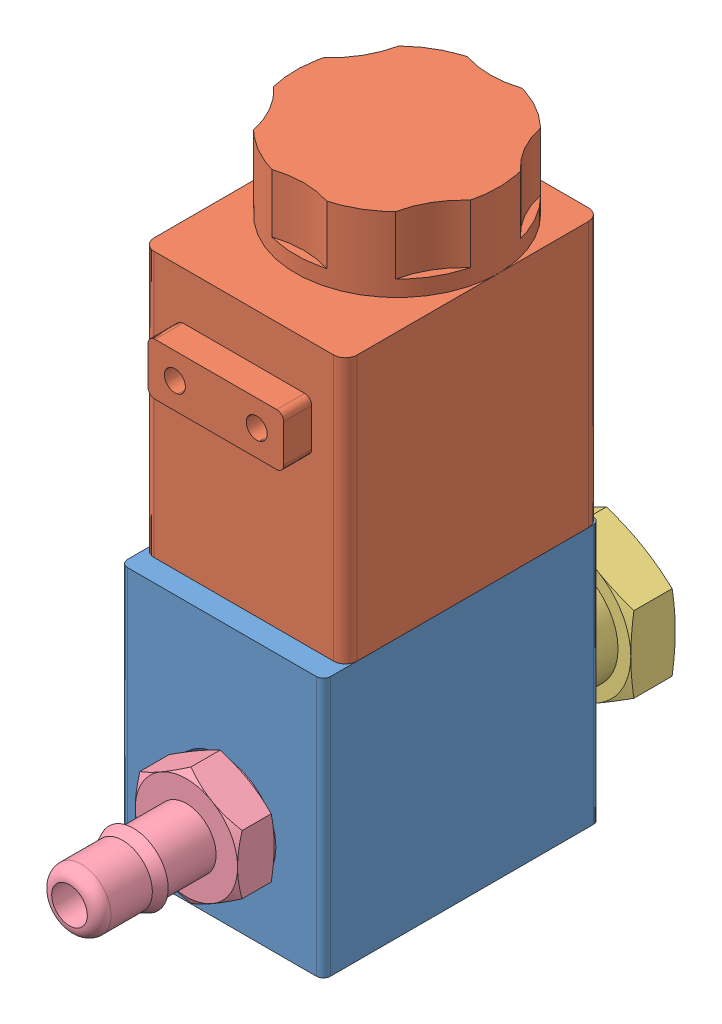
SolidWorks assembly Solenoid Valve Assembly REV1, configuration Default. Lengths in mm.
Overall size (22.05 65.07 58.93).
4 component instances, 4 part files, 9 mates.
Components (placement in the parent):
- Solenoid Valve bottom REV1-1: Solenoid Valve bottom REV1 [Default] at (0.5427 1.4167 38.0636) size (22.05 28.19 30.07)
- Solenoid Valve Top REV1-1: Solenoid Valve Top REV1 [Default] at (0.5427 29.6107 35.676) size (22.05 36.88 30.73)
- Brass Adapter-1: Brass Adapter [Default] at (11.452 11.2084 -4.1526) x (0 0 1) z (-1 0 0) size (14.99 16.48 14.27)
- 5058K294_ALUMINUM BARBED TUBE FITTING-1: 5058K294_ALUMINUM BARBED TUBE FITTING [5058K294] at (11.6806 11.3608 41.6355) x (0 0 1) z (-1 0 0) size (26.24 12.83 11.11)
Mates (geometry in assembly coordinates):
- Coincident1: coincident anti-aligned: plane of Solenoid Valve bottom REV1-1 through (0.5427 29.6107 38.0636) normal (0 1 0); plane of Solenoid Valve Top REV1-1 through (0.5427 29.6107 35.676) normal (0 -1 0)
- Coincident4: coincident aligned: plane of Solenoid Valve bottom REV1-1 through (0.5427 29.6107 7.99) normal (0 0 -1); plane of Solenoid Valve Top REV1-1 through (0.5427 58.4143 7.99) normal (0 0 -1)
- Coincident5: coincident aligned: plane of Solenoid Valve bottom REV1-1 through (22.5899 29.6107 38.0636) normal (1 0 0); plane of Solenoid Valve Top REV1-1 through (22.5899 58.4143 35.676) normal (1 0 0)
- Concentric1: concentric aligned: cylinder of Solenoid Valve bottom REV1-1 through (11.452 11.2084 21.452) axis (0 0 -1) radius 5.7531; cylinder of Brass Adapter-1 through (11.452 11.2084 10.8334) axis (0 0 -1) radius 5.7531
- Parallel1: parallel aligned: plane of Solenoid Valve bottom REV1-1 through (0.5427 29.6107 38.0636) normal (-1 0 0); plane of Brass Adapter-1 through (4.3146 15.3292 0.6734) normal (-1 0 0)
- Lock1: lock: unknown of Solenoid Valve bottom REV1-1; unknown of Brass Adapter-1
- Concentric2: concentric anti-aligned: cylinder of Solenoid Valve bottom REV1-1 through (11.6806 11.3608 24.6016) axis (0 0 1) radius 5.7531; cylinder of 5058K294_ALUMINUM BARBED TUBE FITTING-1 through (11.6806 11.3608 41.6355) axis (0 0 -1) radius 3.2258
- Parallel2: parallel aligned: plane of Solenoid Valve bottom REV1-1 through (0.5427 29.6107 38.0636) normal (-1 0 0); plane of 5058K294_ALUMINUM BARBED TUBE FITTING-1 through (6.1244 14.5687 42.0324) normal (-1 0 0)
- Coincident8: coincident anti-aligned: plane of Solenoid Valve bottom REV1-1 through (0.5427 29.6107 38.0636) normal (0 0 1); plane of 5058K294_ALUMINUM BARBED TUBE FITTING-1 through (6.1244 20.9845 38.0636) normal (0 0 -1)
